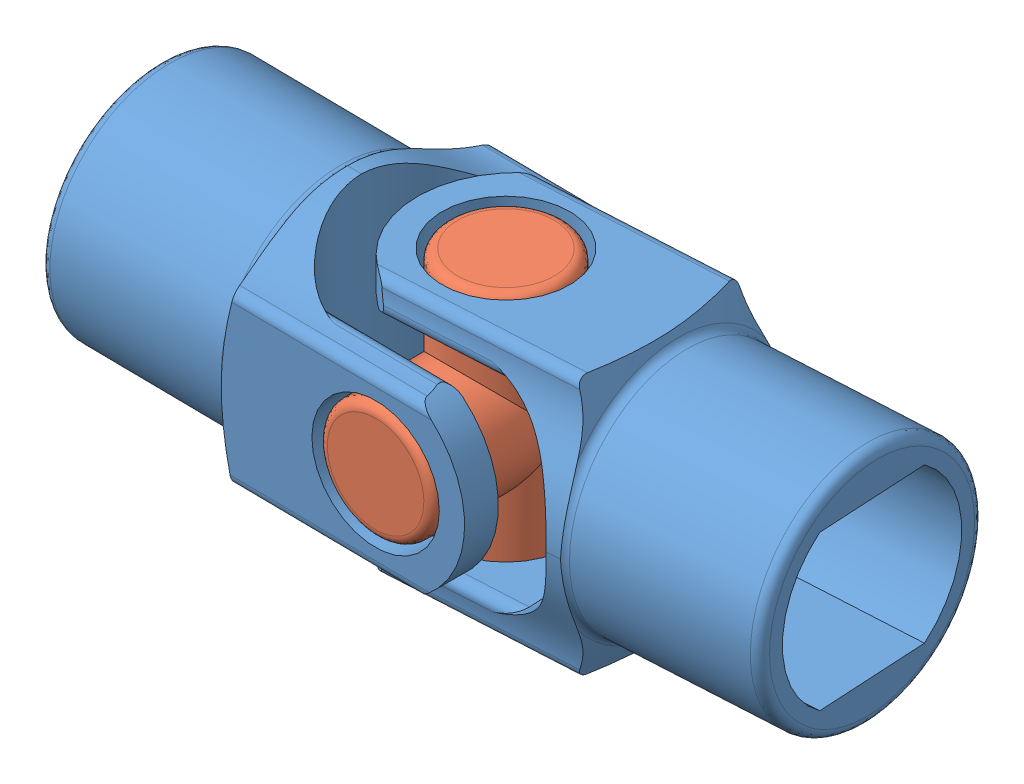
SolidWorks assembly DD_UJoint, configuration Default. Lengths in mm.
Overall size (92.46 35.09 37.57).
3 component instances, 2 part files, 4 mates.
Components (placement in the parent):
- Yoke2-1: Yoke2 [Default] at (19.4106 32.9049 48.0039) x (-0.998451 0 0.055647) z (0 1 0) size (57.4 34.43 34.29)
- UJoint-1: UJoint [Default] at (28.0636 32.9049 30.3767) x (0 1 0) z (0 0 1) size (34.29 15.24 34.29)
- Yoke2-2: Yoke2 [Default] at (36.7295 32.8055 47.5217) x (0.999934 -0.011469 0) z (0 0 1) size (57.4 34.43 34.29)
Mates (geometry in assembly coordinates):
- Concentric2: concentric aligned: cylinder of Yoke2-1 through (28.0636 15.7599 47.5217) axis (0 1 0) radius 8.382; cylinder of UJoint-1 through (28.0636 15.7599 47.5217) axis (0 1 0) radius 7.62
- Coincident2: coincident aligned: plane of Yoke2-1 through (74.3022 50.0499 56.1002) normal (0 1 0); plane of UJoint-1 through (28.0636 50.0499 47.5217) normal (0 1 0)
- Concentric3: concentric aligned: circle of UJoint-1; circle of Yoke2-2
- Coincident3: coincident aligned: plane of UJoint-1 through (28.0636 32.9049 64.6667) normal (0 0 1); plane of Yoke2-2 through (-17.4952 44.5664 64.6667) normal (0 0 1)
